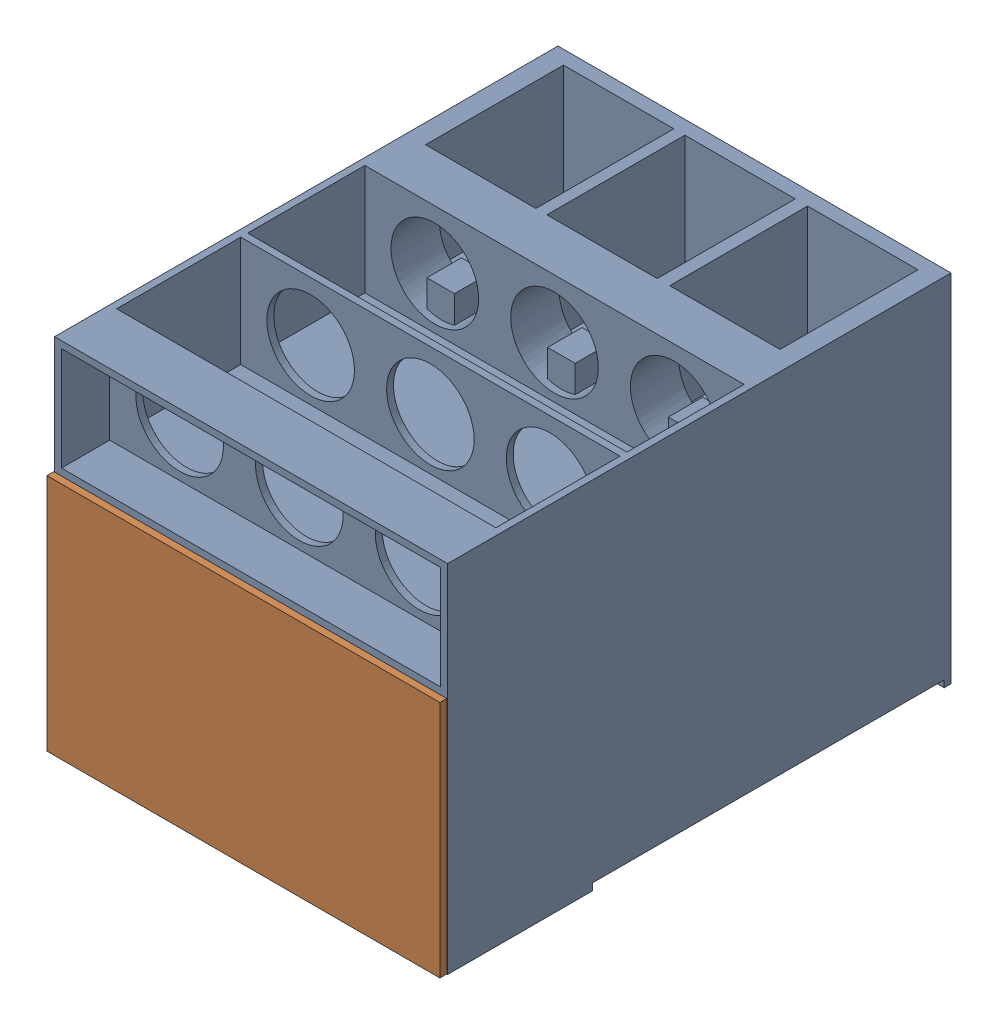
SolidWorks assembly Assem1, configuration Default. Lengths in mm.
Overall size (285.5 258 370).
2 component instances, 2 part files, 4 mates.
Components (placement in the parent):
- part 7 box-1: part 7 box [Default] at (91.0444 -7.7195 81.6739) size (285 258 365)
- part 2 machine box  cap-1: part 2 machine box  cap [Default] at (105.7058 -48.206 451.6739) x (-1 0 0) z (0 0 -1) size (285 173 35)
Mates (geometry in assembly coordinates):
- Coincident1: coincident: plane of part 7 box-1 through (237.9328 16.6331 346.6739) normal (-1 0 0); plane of part 2 machine box  cap-1 through (237.9328 16.6331 417.563) normal (1 0 0)
- Coincident2: coincident: plane of part 7 box-1 through (-37.0672 -146.3669 346.6739) normal (0 1 0); plane of part 2 machine box  cap-1 through (237.9328 -146.3669 417.563) normal (0 -1 0)
- Parallel1: parallel: plane of part 7 box-1 through (-37.0672 16.6331 346.6739) normal (1 0 0); plane of part 2 machine box  cap-1 through (-37.5672 16.6331 417.563) normal (-1 0 0)
- Coincident5: coincident anti-aligned: plane of part 7 box-1 through (91.0444 -7.7195 446.6739) normal (0 0 1); plane of part 2 machine box  cap-1 through (105.7058 -48.206 446.6739) normal (0 0 -1)
